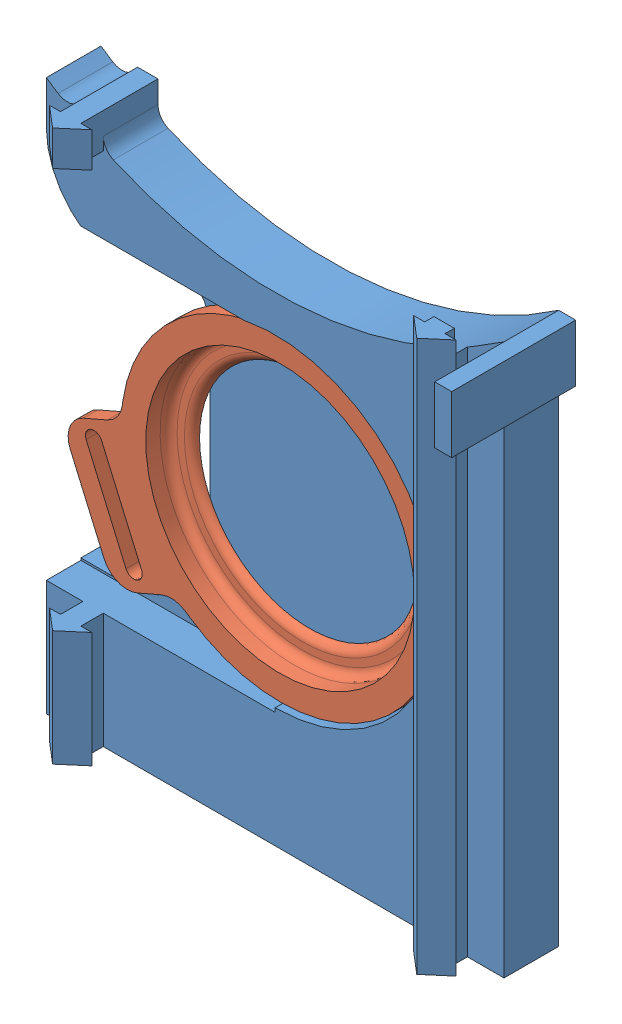
SolidWorks assembly Assem1, configuration Default. Lengths in mm.
Overall size (59.24 69 14.63).
2 component instances, 2 part files, 2 mates.
Components (placement in the parent):
- partealta-1: partealta [Predeterminado] at (-38.3053 -69.8123 11.981) size (56 65 14.63)
- portamoneda-1: portamoneda [Default] at (-37.1623 -1.6468 17.8564) x (-0.398367 0.917226 0) z (-0.917226 -0.398367 0) size (37.5 3.5 43.57)
Mates (geometry in assembly coordinates):
- Coincident1: coincident: plane of assembly; plane of assembly; plane of partealta-1 through (-37.1623 17.0501 14.3564) normal (0 0 1); plane of portamoneda-1 through (-37.1623 -1.6468 14.3564) normal (0 0 -1)
- Concentric1: concentric: circle of assembly; circle of assembly; circle of partealta-1; circle of portamoneda-1
